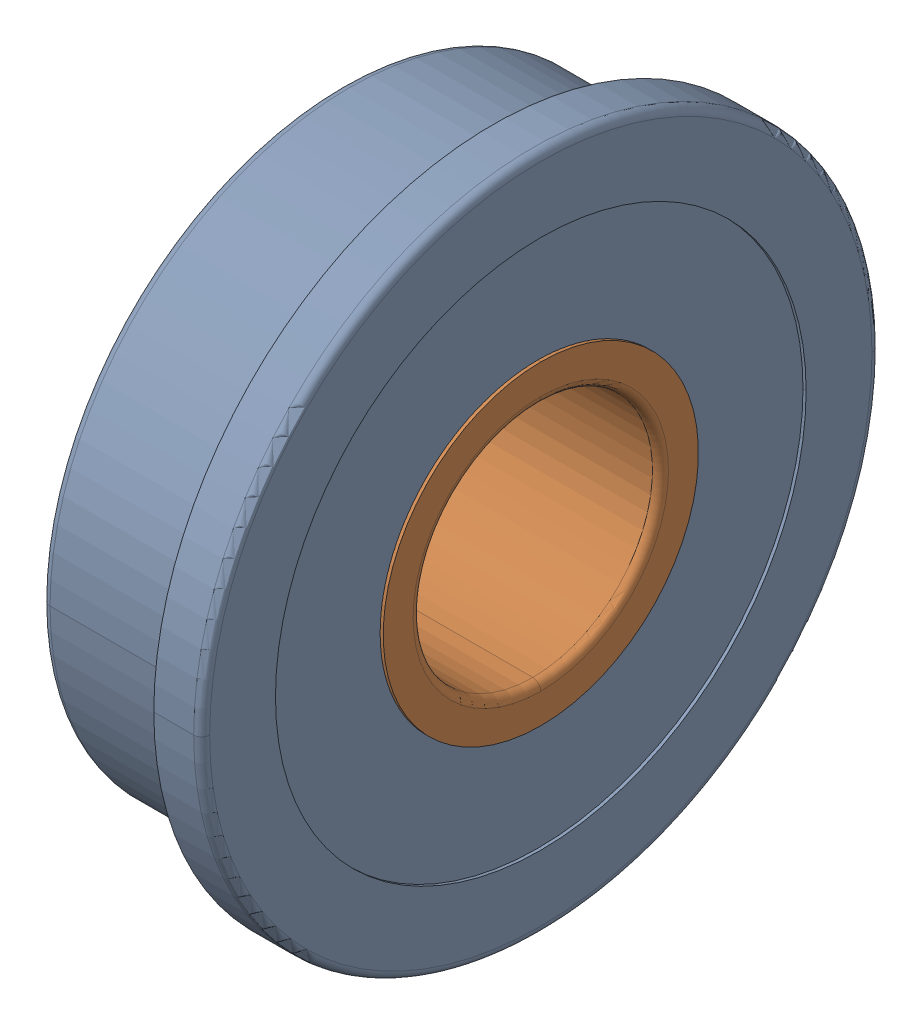
SolidWorks assembly F696ZZ1, configuration Default. Lengths in mm.
Overall size (5 17 17).
13 component instances, 5 part files, 0 mates.
Components (placement in the parent):
- _F696ZZ1_Outer_Ring_2-1: _F696ZZ1_Outer_Ring_2 [Default] at origin size (5 17 17)
- _F696ZZ1_Inner_Ring_4-1: _F696ZZ1_Inner_Ring_4 [Default] x (1 0 0) z (0 -1 0) size (5 8.55 8.55)
- _F696ZZ1_Shield1_6-1: _F696ZZ1_Shield1_6 [Default] at (0.625 0 0) x (-1 0 0) z (0 -1 0) size (0.23 13.3 13.3)
- _F696ZZ1_Ball_8-1: _F696ZZ1_Ball_8 [Default] at (2.5 0 5.25) x (1 0 0) z (0 -1 0) size (2.7 2.7 2.7)
- _F696ZZ1_Ball_8-2: _F696ZZ1_Ball_8 [Default] at (2.5 -3.3746 4.0217) x (1 0 0) z (0 -1 0) size (2.7 2.7 2.7)
- _F696ZZ1_Ball_8-3: _F696ZZ1_Ball_8 [Default] at (2.5 -5.1702 0.9117) x (1 0 0) z (0 -1 0) size (2.7 2.7 2.7)
- _F696ZZ1_Ball_8-4: _F696ZZ1_Ball_8 [Default] at (2.5 -4.5466 -2.625) x (1 0 0) z (0 -1 0) size (2.7 2.7 2.7)
- _F696ZZ1_Ball_8-5: _F696ZZ1_Ball_8 [Default] at (2.5 -1.7956 -4.9334) x (1 0 0) z (0 -1 0) size (2.7 2.7 2.7)
- _F696ZZ1_Ball_8-6: _F696ZZ1_Ball_8 [Default] at (2.5 1.7956 -4.9334) x (1 0 0) z (0 -1 0) size (2.7 2.7 2.7)
- _F696ZZ1_Ball_8-7: _F696ZZ1_Ball_8 [Default] at (2.5 4.5466 -2.625) x (1 0 0) z (0 -1 0) size (2.7 2.7 2.7)
- _F696ZZ1_Ball_8-8: _F696ZZ1_Ball_8 [Default] at (2.5 5.1702 0.9117) x (1 0 0) z (0 -1 0) size (2.7 2.7 2.7)
- _F696ZZ1_Ball_8-9: _F696ZZ1_Ball_8 [Default] at (2.5 3.3746 4.0217) x (1 0 0) z (0 -1 0) size (2.7 2.7 2.7)
- _F696ZZ1_Shield2_18-1: _F696ZZ1_Shield2_18 [Default] at origin size (0.23 13.3 13.3)
